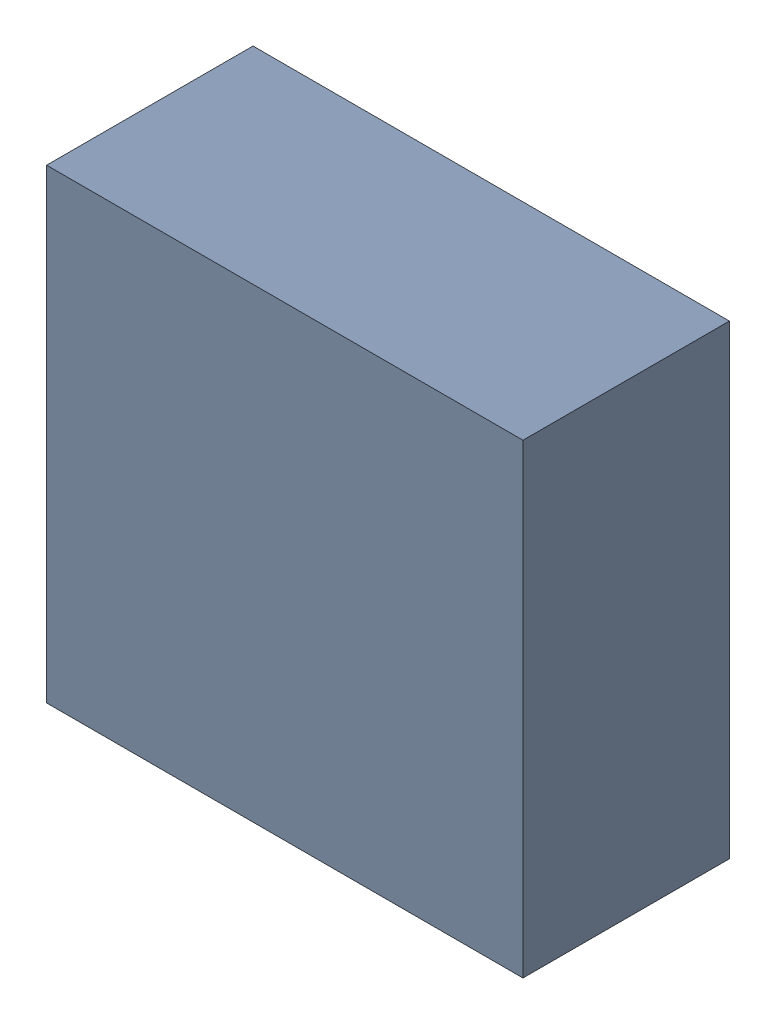
SolidWorks assembly P2, configuration Default. Lengths in mm.
Overall size (8.95 8.75 3.88).
2 component instances, 1 part files, 0 mates.
Components (placement in the parent):
- 898053176-1: 898053176 [Default] at (43.35 4.3638 0) size (8.95 8.75 3.88)
  - Extruded_6-1: Extruded_6 [Default] at origin size (8.95 8.75 3.88)
